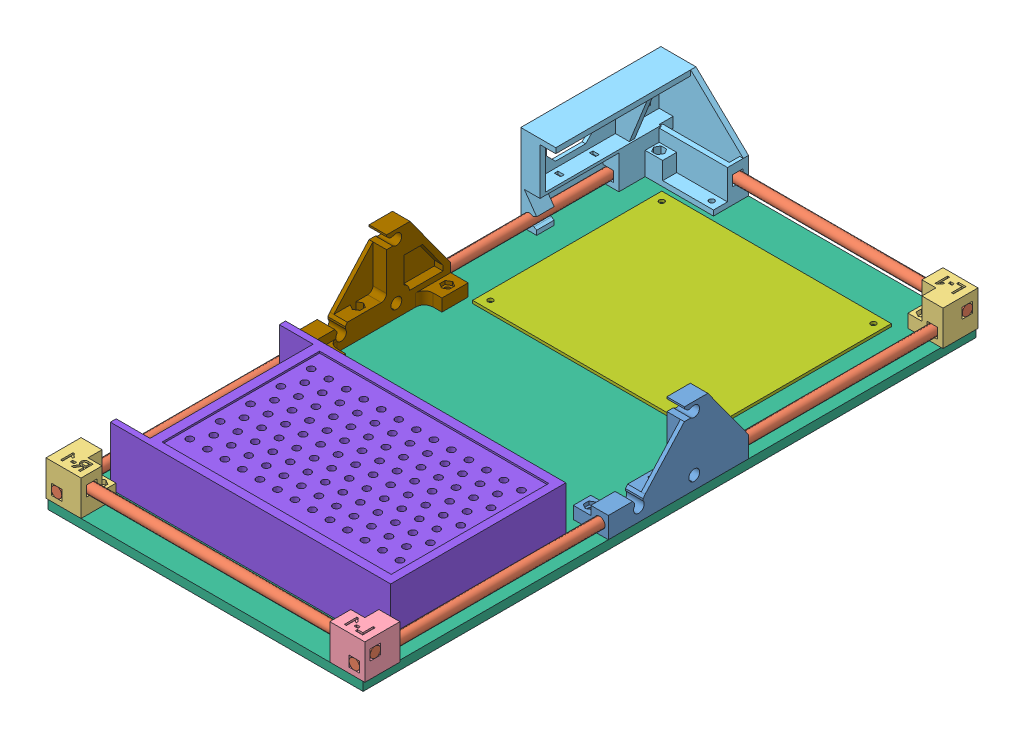
SolidWorks assembly SubMontagem Pés, configuration Valor predeterminado. Lengths in mm.
Overall size (182 53.8 350).
17 component instances, 10 part files, 41 mates.
Components (placement in the parent):
- pé lateral outro-1: pé lateral outro [Valor predeterminado] at (80 0 0) size (20 44 80)
- direito pé lateral outro-1: direito pé lateral outro [Valor predeterminado] at (-80 0 0) x (-1 0 0) z (0 0 -1) (suppressed, hidden)
- Barra roscada 6mm-1: Barra roscada 6mm [150 x6mm roscada] at (-85 6 30) size (6 6 150)
- Barra roscada 6mm-2: Barra roscada 6mm [150 x6mm roscada] at (85 6 30) size (6 6 150)
- Barra roscada 6mm-3: Barra roscada 6mm [150 x6mm roscada] at (85 6 -170) size (6 6 150)
- Barra roscada 6mm-4: Barra roscada 6mm [150 x6mm roscada] at (-85 6 -170) size (6 6 150)
- Nova cantoneira direita-1: Nova cantoneira direita [Valor predeterminado] at (-91 0 140) x (0 0 1) z (-1 0 0) size (40 20 20)
- Nova cantoneira direita-2: Nova cantoneira direita [Nova cantoneira direita] at (51 0 -170) x (0 0 1) z (-1 0 0) size (20 20 40)
- EspelharNova cantoneira direita-4: EspelharNova cantoneira direita [Nova cantoneira direita] at (51 0 180) x (0 0 -1) z (1 0 0) size (20 20 40)
- cantoneira dir-1: cantoneira dir [Valor predeterminado] at (-90 1 -170) x (0 0 1) z (-1 0 0) size (80 48.8 50)
- Barra roscada 6mm-5: Barra roscada 6mm [180x 6mm] at (91 12 174) x (0 -0.903404 -0.428791) z (-1 0 0) size (6 6 180)
- Barra roscada 6mm-6: Barra roscada 6mm [180x 6mm] at (91 12 -164) x (0 -0.903404 -0.428791) z (-1 0 0) size (6 6 180)
- base acrilica-1: base acrilica [Valor predeterminado] at (0 -5 5) size (180 5 350)
- SubEletronica-1: SubEletronica [Valor predeterminado] at (14.732 0 -29) x (0 0 1) z (-1 0 0) size (303 34 160)
  - PCI Gen7br1.2-1: PCI Gen7br1.2 [Valor predeterminado] at (-63 0 14.732) x (0 0 1) z (-1 0 0) size (131 1.6 108)
  - Fonte chaveada 120w_12V_10A_dimensões-1: Fonte chaveada 120w_12V_10A_dimensões [Valor predeterminado] at (136 0 12) x (0 0 -1) z (1 0 0) size (160 34 100)
- Espelharpé lateral outro-2: Espelharpé lateral outro [Valor predeterminado] at (-80 0 0) x (-1 0 0) z (0 0 -1) size (20 44 80)
Mates (geometry in assembly coordinates):
- Coincidente1: coincident anti-aligned: plane of pé lateral outro-1 through (90 0 -74.6033) normal (0 -1 0); plane of assembly through (0 0 0) normal (0 1 0)
- Distância1: distance = 90 mm aligned: plane of assembly through (0 0 0) normal (1 0 0); plane of pé lateral outro-1 through (90 12.5553 -74.6033) normal (1 0 0)
- Coincidente3: coincident aligned: plane of pé lateral outro-1 through (80 0 0) normal (0 0 1); plane of assembly through (0 0 0) normal (0 0 1)
- Paralelo1: parallel anti-aligned: plane of pé lateral outro-1 through (80 12.5553 -74.6033) normal (-1 0 0); plane of direito pé lateral outro-1 through (-80 12.5553 -74.6033) normal (1 0 0)
- Coincidente5: coincident aligned: plane of pé lateral outro-1 through (90 0 -74.6033) normal (0 -1 0); plane of direito pé lateral outro-1 through (-90 0 -74.6033) normal (0 -1 0)
- Concêntrico1: concentric anti-aligned: cylinder of pé lateral outro-1 through (90 7.43 -9) axis (-1 0 0) radius 3.1; cylinder of direito pé lateral outro-1 through (-90 7.43 -9) axis (1 0 0) radius 3
- Distância2: distance = 80 mm aligned: plane of assembly through (0 0 0) normal (1 0 0); plane of direito pé lateral outro-1 through (-80 12.5553 -74.6033) normal (1 0 0)
- Coincidente7: coincident anti-aligned: plane of direito pé lateral outro-1 through (-85 6 30) normal (0 0 1); plane of Barra roscada 6mm-1 through (-85 6 30) normal (0 0 -1)
- Concêntrico2: concentric anti-aligned: circle of direito pé lateral outro-1; cylinder of Barra roscada 6mm-1 through (-85 6 180) axis (0 0 -1) radius 3
- Coincidente9: coincident anti-aligned: plane of pé lateral outro-1 through (85 6 30) normal (0 0 1); plane of Barra roscada 6mm-2 through (85 6 30) normal (0 0 -1)
- Concêntrico3: concentric anti-aligned: cylinder of pé lateral outro-1 through (85 6 30) axis (0 0 1) radius 3.1; cylinder of Barra roscada 6mm-2 through (85 6 180) axis (0 0 -1) radius 3
- Coincidente10: coincident anti-aligned: plane of pé lateral outro-1 through (85 6 -20) normal (0 0 -1); plane of Barra roscada 6mm-3 through (85 6 -20) normal (0 0 1)
- Concêntrico4: concentric aligned: cylinder of pé lateral outro-1 through (85 6 -20) axis (0 0 -1) radius 3.1; cylinder of Barra roscada 6mm-3 through (85 6 -20) axis (0 0 -1) radius 3
- Coincidente11: coincident anti-aligned: plane of direito pé lateral outro-1 through (-85 6 -20) normal (0 0 -1); plane of Barra roscada 6mm-4 through (-85 6 -20) normal (0 0 1)
- Concêntrico5: concentric aligned: cylinder of direito pé lateral outro-1 through (-85 6 -20) axis (0 0 -1) radius 3; cylinder of Barra roscada 6mm-4 through (-85 6 -20) axis (0 0 -1) radius 3
- Paralelo2: parallel aligned: plane of direito pé lateral outro-1 through (-90 12.5553 40) normal (0 0 1); plane of Nova cantoneira direita-1 through (-81 20 180) normal (0 0 1)
- Coincidente22: coincident aligned: plane of Barra roscada 6mm-1 through (-85 6 180) normal (0 0 1); plane of Nova cantoneira direita-1 through (-81 20 180) normal (0 0 1)
- Paralelo3: parallel aligned: plane of direito pé lateral outro-1 through (-90 0 -74.6033) normal (0 -1 0); plane of Nova cantoneira direita-1 through (-81 0 192.1414) normal (0 -1 0)
- Coincidente16: coincident aligned: plane of direito pé lateral outro-1 through (-90 0 -74.6033) normal (0 -1 0); plane of Nova cantoneira direita-1 through (-81 0 192.1414) normal (0 -1 0)
- Paralelo4: parallel anti-aligned: plane of pé lateral outro-1 through (90 12.5553 -40) normal (0 0 -1); plane of Nova cantoneira direita-2 through (81 20 -150) normal (0 0 1)
- Coincidente18: coincident aligned: plane of pé lateral outro-1 through (90 0 -74.6033) normal (0 -1 0); plane of Nova cantoneira direita-2 through (81 0 -182.1414) normal (0 -1 0)
- Distância4: distance = 1 mm aligned: plane of Nova cantoneira direita-2 through (91 20 -182.1414) normal (1 0 0); plane of pé lateral outro-1 through (90 12.5553 -74.6033) normal (1 0 0)
- Coincidente21: coincident aligned: plane of Barra roscada 6mm-3 through (85 6 -170) normal (0 0 -1); plane of Nova cantoneira direita-2 through (81 20 -170) normal (0 0 -1)
- Paralelo6: parallel aligned: plane of direito pé lateral outro-1 through (-90 12.5553 -74.6033) normal (-1 0 0); plane of cantoneira dir-1 through (-90 0 -170) normal (-1 0 0)
- Coincidente25: coincident aligned: plane of direito pé lateral outro-1 through (-90 0 -74.6033) normal (0 -1 0); plane of cantoneira dir-1 through (-80 0 -135) normal (0 -1 0)
- Concêntrico6: concentric anti-aligned: cylinder of Barra roscada 6mm-4 through (-85 6 -20) axis (0 0 -1) radius 3; circle of cantoneira dir-1
- Coincidente27: coincident aligned: plane of Barra roscada 6mm-4 through (-85 6 -170) normal (0 0 -1); plane of cantoneira dir-1 through (-90 0 -170) normal (0 0 -1)
- Coincidente28: coincident aligned: plane of EspelharNova cantoneira direita-4 through (91 20 192.1414) normal (1 0 0); plane of Barra roscada 6mm-5 through (91 12 174) normal (1 0 0)
- Tangente2: tangent anti-aligned: plane of EspelharNova cantoneira direita-4 through (91 15 171) normal (0 -1 0); cylinder of Barra roscada 6mm-5 through (-89 12 174) axis (1 0 0) radius 3
- Tangente3: tangent anti-aligned: plane of EspelharNova cantoneira direita-4 through (91 15 177) normal (0 0 -1); cylinder of Barra roscada 6mm-5 through (-89 12 174) axis (1 0 0) radius 3
- Coincidente29: coincident aligned: plane of Nova cantoneira direita-2 through (91 20 -182.1414) normal (1 0 0); plane of Barra roscada 6mm-6 through (91 12 -164) normal (1 0 0)
- Tangente4: tangent anti-aligned: plane of Nova cantoneira direita-2 through (91 15 -167) normal (0 0 1); cylinder of Barra roscada 6mm-6 through (-89 12 -164) axis (1 0 0) radius 3
- Tangente5: tangent anti-aligned: plane of Nova cantoneira direita-2 through (91 9 -161) normal (0 1 0); cylinder of Barra roscada 6mm-6 through (-89 12 -164) axis (1 0 0) radius 3
- Coincidente30: coincident anti-aligned: plane of cantoneira dir-1 through (-80 0 -135) normal (0 -1 0); plane of base acrilica-1 through (90 0 180) normal (0 1 0)
- Largura1: width: plane of pé lateral outro-1 through (90 12.5553 -74.6033) normal (1 0 0); plane of direito pé lateral outro-1 through (-90 12.5553 -74.6033) normal (-1 0 0); plane of base acrilica-1 through (90 0 -170) normal (1 0 0); plane of base acrilica-1 through (-90 0 -170) normal (-1 0 0)
- Largura2: width: plane of cantoneira dir-1 through (-90 0 -170) normal (0 0 -1); plane of Nova cantoneira direita-1 through (-81 20 180) normal (0 0 1); plane of base acrilica-1 through (-90 0 -170) normal (0 0 -1); plane of base acrilica-1 through (-90 0 180) normal (0 0 1)
- Tangente6: tangent anti-aligned: cylinder of Barra roscada 6mm-1 through (-85 6 180) axis (0 0 -1) radius 3; plane of Nova cantoneira direita-1 through (-88 9 180) normal (1 0 0)
- Coincidente31: coincident anti-aligned: plane of base acrilica-1 through (90 0 180) normal (0 1 0); plane of SubEletronica-1/Fonte chaveada 120w_12V_10A_dimensões-1 through (82.732 0 157) normal (0 -1 0)
- Paralelo7: parallel aligned: plane of direito pé lateral outro-1 through (-90 12.5553 -74.6033) normal (-1 0 0); plane of SubEletronica-1/Fonte chaveada 120w_12V_10A_dimensões-1 through (-79.6638 33 58.4381) normal (-1 0 0)
- Distância5: distance = 4.5 mm anti-aligned: plane of SubEletronica-1/PCI Gen7br1.2-1 through (65.5 1.6 -38) normal (1 0 0); plane of pé lateral outro-1 through (70 -70.3789 4.1448) normal (-1 0 0)
- Distância6: distance = 3 mm anti-aligned: plane of SubEletronica-1/Fonte chaveada 120w_12V_10A_dimensões-1 through (-77.268 33 157) normal (0 0 1); plane of Nova cantoneira direita-1 through (-81 20 160) normal (0 0 -1)
